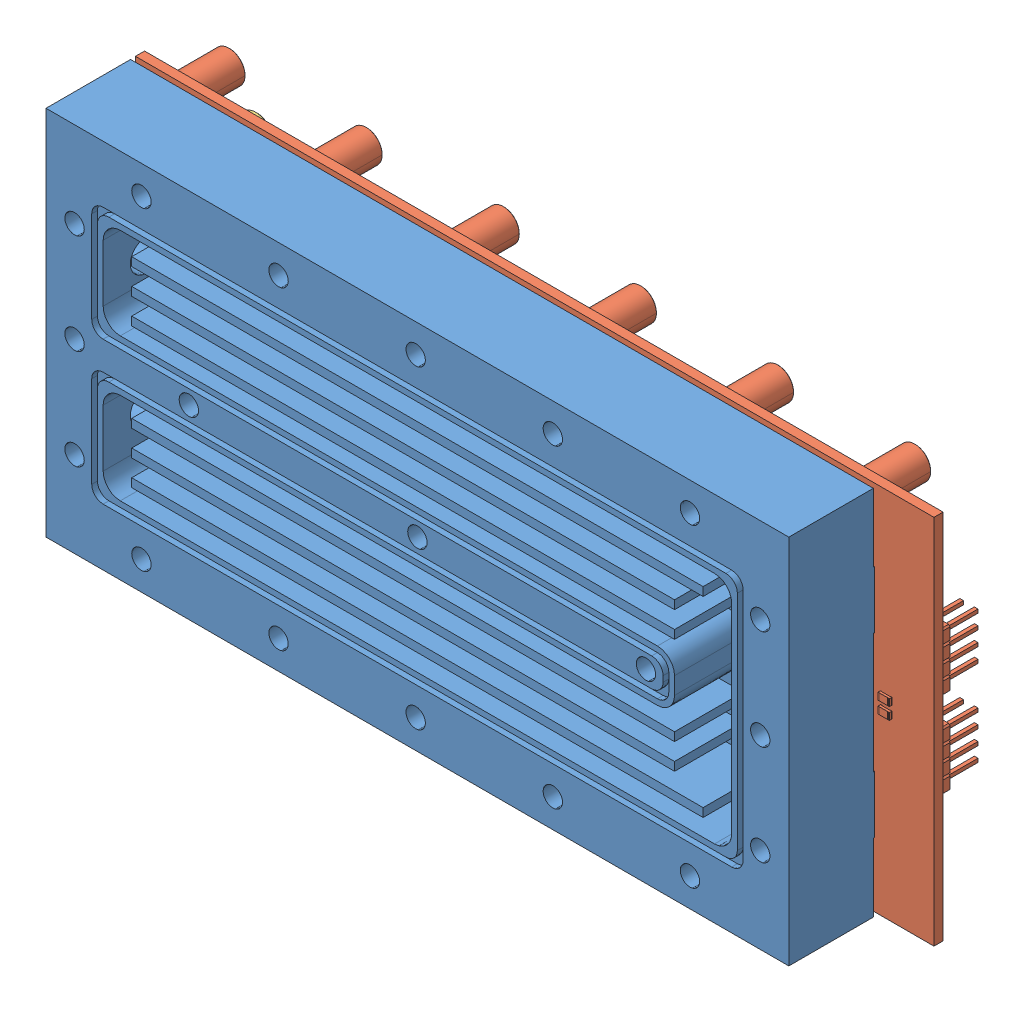
SolidWorks assembly Assemblage31, configuration Défaut. Lengths in mm.
Overall size (139.75 65 27.43).
4 component instances, 3 part files, 7 mates.
Components (placement in the parent):
- EKO_Miner_AsicBoard-BM13xx Heatsink Version C 01A-1: EKO_Miner_AsicBoard-BM13xx Heatsink Version C 01A [Défaut] at (-94.2291 -27.0284 134.868) size (130 65 15)
- EKO_Miner_AsicBoard-10xBM1370-01A-1: EKO_Miner_AsicBoard-10xBM1370-01A [Défaut] at (45.4709 37.9716 132.368) x (-1 0 0) z (0 0 1) size (139.75 65 12.43)
- CHC3 M3x6mm-1: CHC3 M3x6mm [M3X6mm] at (18.4709 -22.0284 129.368) x (0.79942 0.600772 0) z (0 0 -1) size (5.5 5.5 9.19)
- CHC3 M3x6mm-2: CHC3 M3x6mm [M3X6mm] at (-77.5291 32.9716 129.368) x (-0.997347 -0.072796 0) z (0 0 -1) size (5.5 5.5 9.19)
Mates (geometry in assembly coordinates):
- Coaxiale1: concentric anti-aligned: cylinder of EKO_Miner_AsicBoard-BM13xx Heatsink Version C 01A-1 through (-77.5291 32.9716 149.668) axis (0 0 1) radius 1.7; cylinder of EKO_Miner_AsicBoard-10xBM1370-01A-1 through (-77.5291 32.9716 132.323) axis (0 0 -1) radius 1.6
- Coïncidente4: coincident anti-aligned: plane of EKO_Miner_AsicBoard-BM13xx Heatsink Version C 01A-1 through (-94.2291 -27.0284 134.668) normal (0 0 -1); plane of EKO_Miner_AsicBoard-10xBM1370-01A-1 through (18.4709 20.9716 134.668) normal (0 0 1)
- Coaxiale4: concentric anti-aligned: cylinder of EKO_Miner_AsicBoard-BM13xx Heatsink Version C 01A-1 through (18.4709 -22.0284 149.668) axis (0 0 1) radius 1.7; cylinder of EKO_Miner_AsicBoard-10xBM1370-01A-1 through (18.4709 -22.0284 132.323) axis (0 0 -1) radius 1.6
- Coaxiale5: concentric aligned: cylinder of EKO_Miner_AsicBoard-10xBM1370-01A-1 through (18.4709 -22.0284 132.323) axis (0 0 -1) radius 1.6; cylinder of CHC3 M3x6mm-1 through (18.4709 -22.0284 129.368) axis (0 0 -1) radius 1.5
- Coïncidente2: coincident anti-aligned: plane of EKO_Miner_AsicBoard-10xBM1370-01A-1 through (45.4709 37.9716 132.368) normal (0 0 -1); plane of CHC3 M3x6mm-1 through (19.9939 -24.0549 132.368) normal (0 0 1)
- Coaxiale6: concentric aligned: cylinder of EKO_Miner_AsicBoard-10xBM1370-01A-1 through (-77.5291 32.9716 132.323) axis (0 0 -1) radius 1.6; cylinder of CHC3 M3x6mm-2 through (-77.5291 32.9716 129.368) axis (0 0 -1) radius 1.5
- Coïncidente3: coincident anti-aligned: plane of EKO_Miner_AsicBoard-10xBM1370-01A-1 through (45.4709 37.9716 132.368) normal (0 0 -1); plane of CHC3 M3x6mm-2 through (-77.7136 35.4999 132.368) normal (0 0 1)
